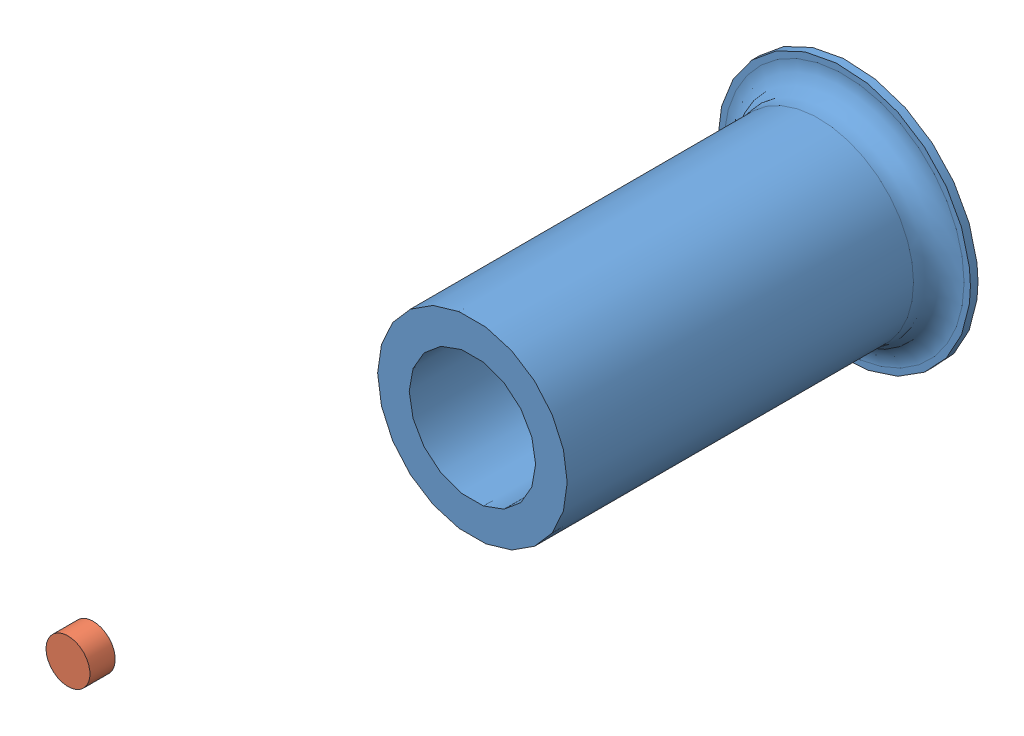
SolidWorks assembly smartPot, configuration Default. Lengths in mm.
Overall size (100 100 310).
2 component instances, 2 part files, 4 mates.
Components (placement in the parent):
- smartPot-1: smartPot [Default] at origin size (100 100 150)
- growLight-1: growLight [Default] at (0 0 300) size (17.39 17.39 10)
Mates (geometry in assembly coordinates):
- Coincident2: coordinate: point of smartPot-1; point of assembly
- Parallel3: parallel aligned: plane of growLight-1 through (0 0 300) normal (0 0 1); plane of assembly through (0 0 0) normal (0 0 1)
- Coincident11: coincident: point of growLight-1; line of assembly
- Distance2: distance = 300 mm: point of growLight-1; plane of assembly
